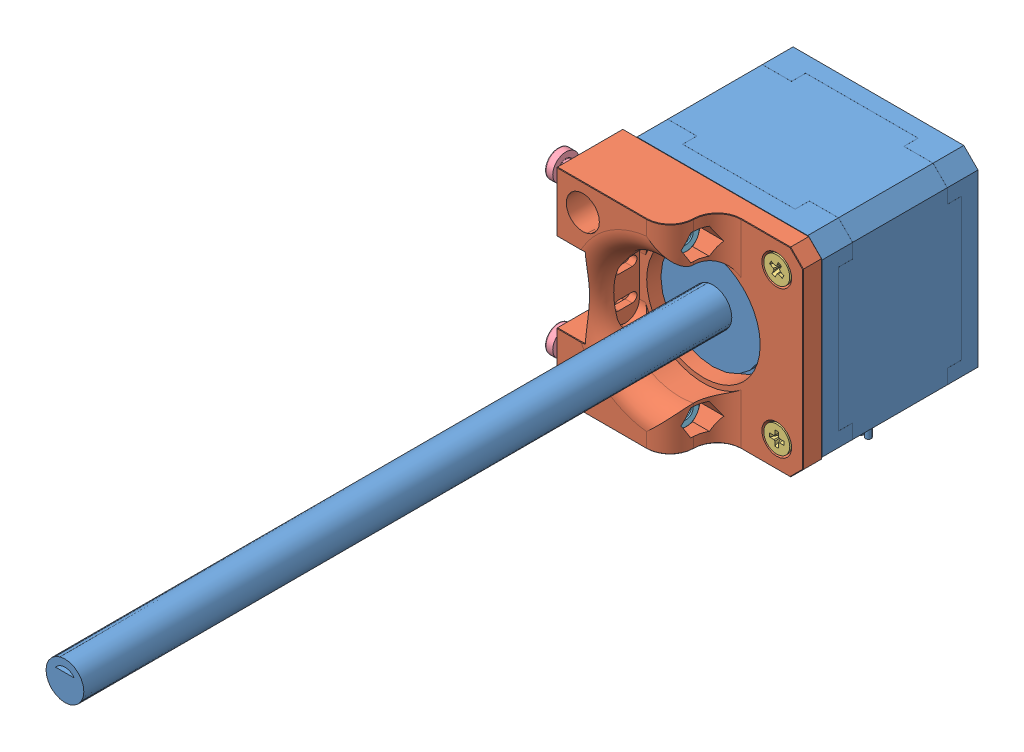
SolidWorks assembly Zmotor autosaved, configuration Default. Lengths in mm.
Overall size (48.45 59.12 172).
10 component instances, 5 part files, 12 mates.
Components (placement in the parent):
- Steper Motor 34mm (42HD0401-135L)-1: Steper Motor 34mm (42HD0401-135L) [Default] at origin size (42.1 59.12 172)
- Z Motor mount-1: Z Motor mount [Valor predeterminado] at (-330.7157 -87.3227 33) x (0 1 0) z (0 0 1) size (42.1 42.1 15.64)
- ISO 7046-1 - M3 x 10 - Z --- 10N-1: ISO 7046-1 - M3 x 10 - Z --- 10N [ISO 7046-1 - M3 x 12 - Z --- 12N] at (-15.5 15.5 37) x (0 0 -1) z (0.999999 0.001551 0) size (12 5.5 5.5)
- ISO 7046-1 - M3 x 10 - Z --- 10N-2: ISO 7046-1 - M3 x 10 - Z --- 10N [ISO 7046-1 - M3 x 12 - Z --- 12N] at (15.5 15.5 37) x (0 0 -1) z (0.444535 0.895762 0) size (12 5.5 5.5)
- ISO 7046-1 - M3 x 10 - Z --- 10N-3: ISO 7046-1 - M3 x 10 - Z --- 10N [ISO 7046-1 - M3 x 12 - Z --- 12N] at (15.5 -15.5 37) x (0 0 -1) z (0.999915 -0.013072 0) size (12 5.5 5.5)
- ISO 7046-1 - M3 x 10 - Z --- 10N-4: ISO 7046-1 - M3 x 10 - Z --- 10N [ISO 7046-1 - M3 x 12 - Z --- 12N] at (-15.5 -15.5 37) x (0 0 -1) z (0.999885 0.015174 0) size (12 5.5 5.5)
- ISO 7045 - M3 x 20 - Z --- 20N-3: ISO 7045 - M3 x 20 - Z --- 20N [ISO 7045 - M3 x 25 - Z --- 25N] at (-27.45 -16.0364 41.0127) x (1 0 0) z (0 -1 0) size (27.35 5.6 5.6)
- ISO 7045 - M3 x 20 - Z --- 20N-4: ISO 7045 - M3 x 20 - Z --- 20N [ISO 7045 - M3 x 25 - Z --- 25N] at (-27.45 16.0364 41.0127) x (1 0 0) z (0 -1 0) size (27.35 5.6 5.6)
- hex thin nut chamfered gradeab_iso-1: hex thin nut chamfered gradeab_iso [Hexagon Thin Nut ISO - 4035 - M3 - N] at (0.35 16.0364 41.0127) x (0 1 0) z (1 0 0) size (5.5 6.35 1.8)
- hex thin nut chamfered gradeab_iso-2: hex thin nut chamfered gradeab_iso [Hexagon Thin Nut ISO - 4035 - M3 - N] at (0.35 -16.0364 41.0127) x (0 1 0) z (1 0 0) size (5.5 6.35 1.8)
Mates (geometry in assembly coordinates):
- Coincidente255: coincident: plane of Steper Motor 34mm (42HD0401-135L)-1 through (21.05 21.05 33) normal (0 0 1); plane of Z Motor mount-1 through (-330.7157 -87.3227 33) normal (0 0 -1)
- Coincidente256: coincident: plane of Steper Motor 34mm (42HD0401-135L)-1 through (-21.05 21.05 33) normal (0 1 0); plane of Z Motor mount-1 through (21.05 21.05 37) normal (0 1 0)
- Coincidente258: coincident: plane of Steper Motor 34mm (42HD0401-135L)-1 through (21.05 -21.05 33) normal (1 0 0); plane of Z Motor mount-1 through (21.05 21.05 37) normal (1 0 0)
- Coincidente259: coincident: cone of Z Motor mount-1 through (-15.5 15.5 37) axis (0 0 -1); cone of ISO 7046-1 - M3 x 10 - Z --- 10N-1 through (-15.5 15.5 36.6) axis (0 0 -1)
- Coincidente260: coincident: cone of Z Motor mount-1 through (15.5 15.5 37) axis (0 0 -1); cone of ISO 7046-1 - M3 x 10 - Z --- 10N-2 through (15.5 15.5 36.6) axis (0 0 -1)
- Coincidente261: coincident: cone of Z Motor mount-1 through (15.5 -15.5 37) axis (0 0 -1); cone of ISO 7046-1 - M3 x 10 - Z --- 10N-3 through (15.5 -15.5 36.6) axis (0 0 -1)
- Coincidente262: coincident: cone of Z Motor mount-1 through (-15.5 -15.5 37) axis (0 0 -1); cone of ISO 7046-1 - M3 x 10 - Z --- 10N-4 through (-15.5 -15.5 36.6) axis (0 0 -1)
- Concentric45: concentric: cylinder of Z Motor mount-1 through (-21.05 16.0364 41.0127) axis (-1 0 0) radius 1.6; cylinder of hex thin nut chamfered gradeab_iso-1 through (-24.6875 16.0364 41.0127) axis (1 0 0) radius 1.5
- Coincident786995: coincident: plane of Z Motor mount-1 through (-1.45 -87.3227 33) normal (1 0 0); plane of hex thin nut chamfered gradeab_iso-1 through (-1.45 16.0364 44.1881) normal (-1 0 0)
- Concentric46: concentric: cylinder of Z Motor mount-1 through (-21.05 -16.0364 41.0127) axis (-1 0 0) radius 1.6; cylinder of hex thin nut chamfered gradeab_iso-2 through (-24.6875 -16.0364 41.0127) axis (1 0 0) radius 1.5
- Coincident786996: coincident: plane of Z Motor mount-1 through (-1.45 -87.3227 33) normal (1 0 0); plane of hex thin nut chamfered gradeab_iso-2 through (-1.45 -16.0364 44.1881) normal (-1 0 0)
- Concentric56: concentric: cylinder of Z Motor mount-1 through (-21.05 16.0364 41.0127) axis (-1 0 0) radius 1.6; cylinder of ISO 7045 - M3 x 20 - Z --- 20N-4 through (-52.85 16.0364 41.0127) axis (-1 0 0) radius 1.5
